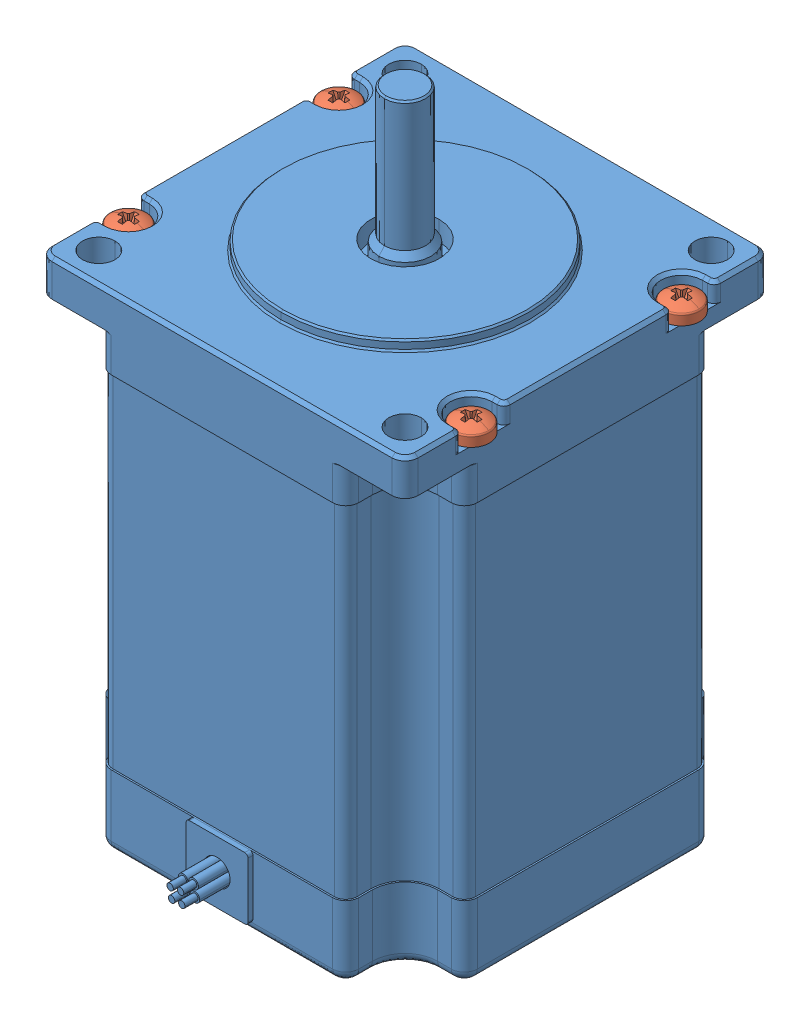
SolidWorks assembly NEMA 23 - 76mm, configuration Default. Lengths in mm.
Overall size (58.2 96.5 63.21).
5 component instances, 2 part files, 0 mates.
Components (placement in the parent):
- NEMA 23 - 76mm.STEP-1: NEMA 23 - 76mm.STEP [Default] at (99.6868 0 0) size (56.21 96.5 63.21)
- pan head cross recess screw_iso_ISO 7045 - M3 x 10 - Z - 10N.STEP-1: pan head cross recess screw_iso_ISO 7045 - M3 x 10 - Z - 10N.STEP [Default] at (125.9868 73.9 -16.15) x (0 -1 0) z (0 0 1) size (12.36 5.6 5.6)
- pan head cross recess screw_iso_ISO 7045 - M3 x 10 - Z - 10N.STEP-2: pan head cross recess screw_iso_ISO 7045 - M3 x 10 - Z - 10N.STEP [Default] at (125.9868 73.9 16.15) x (0 -1 0) z (0 0 1) size (12.36 5.6 5.6)
- pan head cross recess screw_iso_ISO 7045 - M3 x 10 - Z - 10N.STEP-3: pan head cross recess screw_iso_ISO 7045 - M3 x 10 - Z - 10N.STEP [Default] at (73.3868 73.9 16.15) x (0 -1 0) z (0 0 1) size (12.36 5.6 5.6)
- pan head cross recess screw_iso_ISO 7045 - M3 x 10 - Z - 10N.STEP-4: pan head cross recess screw_iso_ISO 7045 - M3 x 10 - Z - 10N.STEP [Default] at (73.3868 73.9 -16.15) x (0 -1 0) z (0 0 1) size (12.36 5.6 5.6)
